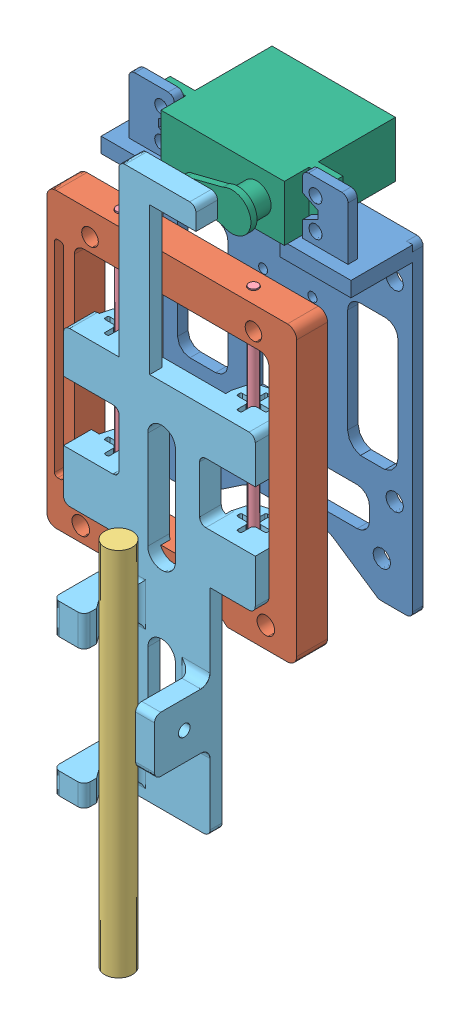
SolidWorks assembly Сборка2, configuration По умолчанию. Lengths in mm.
Overall size (80.98 219.73 74.6).
7 component instances, 6 part files, 13 mates.
Components (placement in the parent):
- axidraw-1: axidraw [По умолчанию] at (31.1199 13.1363 56.6469) size (80.98 124.26 23.4)
- axidraw2-1: axidraw2 [По умолчанию] at (31.1199 13.1363 87.6469) size (80.98 94.88 10)
- ручка-1: ручка [По умолчанию] at (66.5916 37.6655 109.8755) x (0.925079 0 0.379775) z (0 -1 0) size (9 9 120)
- стержень-1: стержень [По умолчанию] at (93.1002 113.5407 92.6469) x (-0.559523 0 -0.828815) z (0 -1 0) size (3 3 90)
- стержень-2: стержень [По умолчанию] at (50.1199 113.6215 92.6469) x (0.249477 0 -0.968381) z (0 -1 0) size (3 3 90)
- axidraw3-1: axidraw3 [По умолчанию] at (112.1002 80.6692 87.6469) x (-1 0 0) z (0 -1 0) size (62.13 34 175)
- мотор-1: мотор [По умолчанию] at (99.5087 136.1363 73.0469) x (1 0 0) z (0 0 -1) size (56 18 44)
Mates (geometry in assembly coordinates):
- Концентричный1: concentric aligned: circle of axidraw-1; circle of axidraw2-1
- Параллельность1: parallel aligned: line of axidraw-1 through (110.1002 118.1363 56.6469) axis (-1 0 0); line of axidraw2-1 through (112.1002 113.2339 87.6469) axis (-1 0 0)
- Расстояние1: distance = 31 mm aligned: plane of axidraw-1 through (31.1199 13.1363 56.6469) normal (0 0 -1); plane of axidraw2-1 through (31.1199 13.1363 87.6469) normal (0 0 -1)
- Параллельность2: parallel aligned: plane of axidraw-1 through (112.1002 13.1363 60.0469) normal (1 0 0); plane of axidraw2-1 through (112.1002 13.1363 97.6469) normal (1 0 0)
- Концентричный2: concentric anti-aligned: circle of стержень-2; circle of axidraw2-1
- Концентричный3: concentric anti-aligned: circle of axidraw2-1; circle of стержень-1
- Концентричный5: concentric aligned: cylinder of стержень-2 through (50.1199 23.6215 92.6469) axis (0 1 0) radius 1.5; cylinder of axidraw3-1 through (50.1199 30.6692 92.6469) axis (0 1 0) radius 1.55
- Концентричный6: concentric aligned: cylinder of стержень-1 through (93.1002 23.5407 92.6469) axis (0 1 0) radius 1.5; cylinder of axidraw3-1 through (93.1002 30.6692 92.6469) axis (0 1 0) radius 1.55
- Совпадение2: coincident anti-aligned: plane of axidraw2-1 through (31.1199 30.6692 97.6469) normal (0 1 0); plane of axidraw3-1 through (112.1002 30.6692 87.6469) normal (0 -1 0)
- Совпадение4: coincident anti-aligned: plane of axidraw-1 through (31.1199 13.1363 73.0469) normal (0 0 -1); plane of мотор-1 through (99.5087 136.1363 73.0469) normal (0 0 1)
- Совпадение5: coincident anti-aligned: plane of axidraw-1 through (31.1199 118.1363 60.0469) normal (0 1 0); plane of мотор-1 through (99.5087 118.1363 70.0469) normal (0 -1 0)
- Касательность2: tangent anti-aligned: cylinder of ручка-1 through (66.5916 -82.3345 109.8755) axis (0 1 0) radius 4.5; plane of axidraw3-1 through (68.1008 25.7696 119.6097) normal (0.809058 0 -0.587729)
- Касательность3: tangent anti-aligned: cylinder of ручка-1 through (66.5916 -82.3345 109.8755) axis (0 1 0) radius 4.5; plane of axidraw3-1 through (91.6822 25.7696 71.3113) normal (0.780847 0 0.624722)
